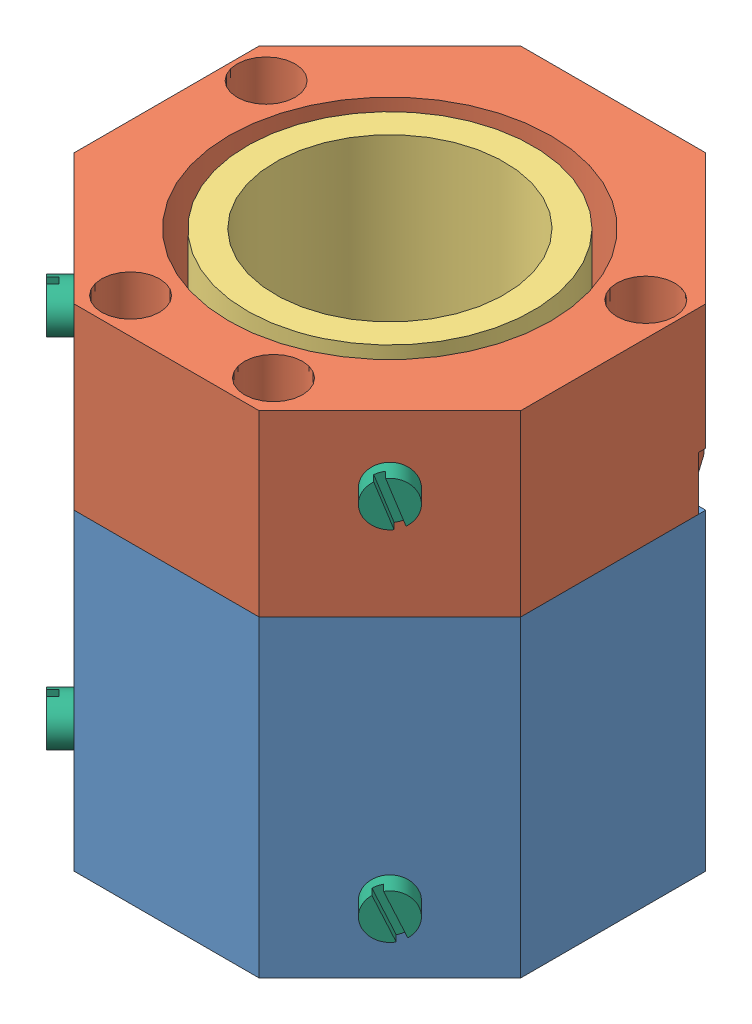
SolidWorks assembly Collimator Allignment Tool, configuration Default. Lengths in mm.
Overall size (53.24 55 52.99).
10 component instances, 7 part files, 19 mates.
Components (placement in the parent):
- CR056-A - Left Collimator Mount-1: CR056-A - Left Collimator Mount [Default] at (3.8775 14.1893 42.3795) size (50 35 50)
- CR057-A - Right Collimator Mount-1: CR057-A - Right Collimator Mount [Default] at (3.8775 69.1893 42.3795) x (-1 0 0) z (0 0 1) size (50 20 50)
- CR058-A - Collimation Tube-1: CR058-A - Collimation Tube [Default] at (3.8775 41.6893 42.3795) x (0.929019 0 -0.370032) z (0.370032 0 0.929019) size (32 55 32)
- CR059-A - Tube Connector-1: CR059-A - Tube Connector [Default] at (-3.9493 41.6893 22.7292) x (0.561705 0.796513 -0.22373) z (0.739975 -0.604622 -0.294735) size (4 13 4)
- CR060-A - Drive Stick-1: CR060-A - Drive Stick [Default] at (-14.0039 41.1893 24.6742) x (0.653645 0.370075 -0.660145) z (-0.260385 0.929002 0.262974) size (4 12 4)
- CR061-A - Spring Bus-1: CR061-A - Spring Bus [Default] at (-15.3558 21.6893 61.6128) x (0.707107 0 -0.707107) z (0.707107 0 0.707107) size (6.5 5 5)
- CR062-A - Polerazation Selector-1: CR062-A - Polerazation Selector [Default] at (-8.6744 41.1893 29.9512) x (-0.7036 0 0.710596) z (0 -1 0) size (15 10 28)
- CR061-A - Spring Bus-2: CR061-A - Spring Bus [Default] at (-15.3558 61.6893 61.6128) x (0.707107 0 -0.707107) z (0.707107 0 0.707107) size (6.5 5 5)
- CR061-A - Spring Bus-4: CR061-A - Spring Bus [Default] at (23.1108 61.6893 61.6128) x (-0.707107 0 -0.707107) z (0.667683 0.329242 -0.667683) size (6.5 5 5)
- CR061-A - Spring Bus-6: CR061-A - Spring Bus [Default] at (23.1108 21.6893 61.6128) x (-0.707107 0 -0.707107) z (0.650538 0.391918 -0.650538) size (6.5 5 5)
Mates (geometry in assembly coordinates):
- Coincident1: coincident: plane of CR056-A - Left Collimator Mount-1 through (-21.1225 49.1893 32.0242) normal (-1 0 0); plane of CR057-A - Right Collimator Mount-1 through (-21.1225 49.1893 52.7348) normal (-1 0 0)
- Coincident2: coincident: plane of CR056-A - Left Collimator Mount-1 through (14.2328 49.1893 17.3795) normal (0 0 -1); plane of CR057-A - Right Collimator Mount-1 through (-6.4779 49.1893 17.3795) normal (0 0 -1)
- Coincident3: coincident: plane of CR056-A - Left Collimator Mount-1 through (3.8775 49.1893 42.3795) normal (0 1 0); plane of CR057-A - Right Collimator Mount-1 through (3.8775 49.1893 42.3795) normal (0 -1 0)
- Concentric1: concentric: cylinder of CR056-A - Left Collimator Mount-1 through (3.8775 14.1883 42.3795) axis (0 1 0) radius 18; cylinder of CR058-A - Collimation Tube-1 through (3.8775 69.1893 42.3795) axis (0 -1 0) radius 16
- Width1: width: plane of CR057-A - Right Collimator Mount-1 through (3.8775 69.1893 42.3795) normal (0 1 0); plane of CR056-A - Left Collimator Mount-1 through (3.8775 14.1893 42.3795) normal (0 -1 0); plane of CR058-A - Collimation Tube-1 through (3.8775 14.1893 42.3795) normal (0 -1 0); plane of CR058-A - Collimation Tube-1 through (3.8775 69.1893 42.3795) normal (0 1 0)
- Width2: width: plane of CR056-A - Left Collimator Mount-1 through (13.2522 26.6893 36.967) normal (0 1 0); plane of CR057-A - Right Collimator Mount-1 through (-5.4972 55.6893 36.967) normal (0 -1 0); plane of CR062-A - Polerazation Selector-1 through (-5.6443 27.1893 36.8214) normal (0 -1 0); plane of CR062-A - Polerazation Selector-1 through (-5.6443 55.1893 36.8214) normal (0 1 0)
- Slot1: slot: cylinder of CR062-A - Polerazation Selector-1 through (-7.1325 27.4393 23.7381) axis (0 -1 0) radius 0.25; cylinder of CR057-A - Right Collimator Mount-1 through (3.8775 55.6893 42.3795) axis (0 -1 0) radius 20; cylinder of CR057-A - Right Collimator Mount-1 through (-14.872 55.6893 31.5545) axis (0 -1 0) radius 1.65
- Slot2: slot: cylinder of CR062-A - Polerazation Selector-1 through (-14.872 27.4393 31.5545) axis (0 -1 0) radius 0.25; cylinder of CR057-A - Right Collimator Mount-1 through (3.8775 55.6893 42.3795) axis (0 -1 0) radius 20; cylinder of CR057-A - Right Collimator Mount-1 through (-14.872 55.6893 31.5545) axis (0 -1 0) radius 1.65
- Concentric2: concentric: cylinder of CR058-A - Collimation Tube-1 through (-2.0434 41.6893 27.5143) axis (0.370032 0 0.929019) radius 2; cylinder of CR059-A - Tube Connector-1 through (0.8611 41.6893 34.8064) axis (0.370032 0 0.929019) radius 2
- Concentric4: concentric: cylinder of CR060-A - Drive Stick-1 through (-22.531 41.1893 16.231) axis (0.710596 0 0.7036) radius 2; cylinder of CR062-A - Polerazation Selector-1 through (-15.7803 41.1893 22.9152) axis (-0.710596 0 -0.7036) radius 1.65
- Coincident4: coincident: plane of CR060-A - Drive Stick-1 through (-14.0039 41.1893 24.6742) normal (0.710596 0 0.7036); plane of CR062-A - Polerazation Selector-1 through (-14.0039 41.1893 24.6742) normal (0.710596 0 0.7036)
- Concentric5: concentric: cylinder of CR056-A - Left Collimator Mount-1 through (-13.8002 21.6893 60.0572) axis (-0.707107 0 0.707107) radius 2.1; cylinder of CR061-A - Spring Bus-1 through (-13.9416 21.6893 60.1986) axis (0.707107 0 -0.707107) radius 2.5
- Coincident5: coincident: circle of CR056-A - Left Collimator Mount-1; plane of CR061-A - Spring Bus-1 through (-10.7596 24.1893 57.0166) normal (0.707107 0 -0.707107)
- Concentric6: concentric: cylinder of CR057-A - Right Collimator Mount-1 through (-13.8002 61.6893 60.0572) axis (-0.707107 0 0.707107) radius 2.1; cylinder of CR061-A - Spring Bus-2 through (-13.9416 61.6893 60.1986) axis (0.707107 0 -0.707107) radius 2.5
- Coincident6: coincident: circle of CR057-A - Right Collimator Mount-1; plane of CR061-A - Spring Bus-2 through (-10.7596 64.1893 57.0166) normal (0.707107 0 -0.707107)
- Concentric7: concentric: cylinder of CR057-A - Right Collimator Mount-1 through (21.5551 61.6893 60.0572) axis (0.707107 0 0.707107) radius 2.1; cylinder of CR061-A - Spring Bus-4 through (21.6966 61.6893 60.1986) axis (-0.707107 0 -0.707107) radius 2.5
- Coincident7: coincident: circle of CR057-A - Right Collimator Mount-1; plane of CR061-A - Spring Bus-4 through (17.9326 64.05 57.5986) normal (-0.707107 0 -0.707107)
- Concentric8: concentric: cylinder of CR056-A - Left Collimator Mount-1 through (21.5551 21.6893 60.0572) axis (0.707107 0 0.707107) radius 2.1; cylinder of CR061-A - Spring Bus-6 through (21.6966 21.6893 60.1986) axis (-0.707107 0 -0.707107) radius 2.5
- Coincident8: coincident: circle of CR056-A - Left Collimator Mount-1; plane of CR061-A - Spring Bus-6 through (17.8218 23.9893 57.7094) normal (-0.707107 0 -0.707107)
